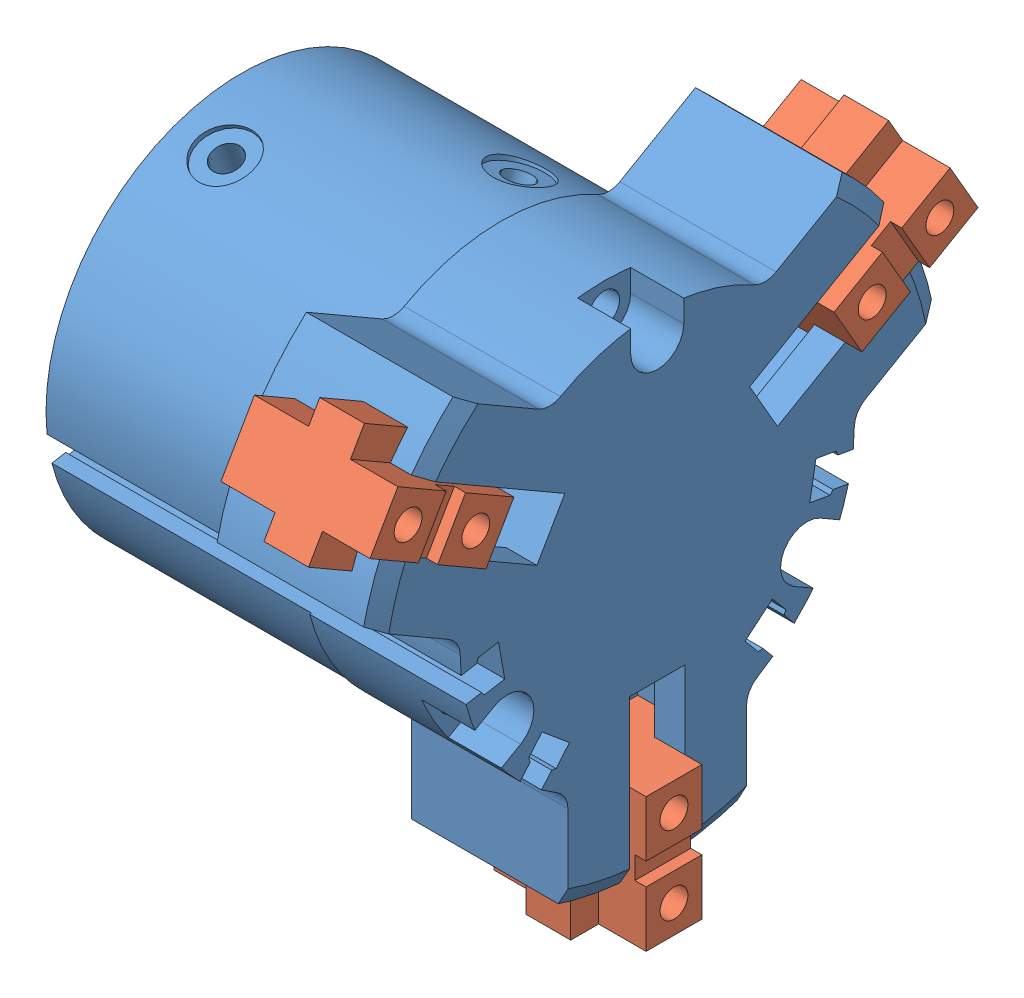
SolidWorks assembly MHSL3-50D, configuration MHSL3-50D. Lengths in mm.
Overall size (77.5 98.66 113.92).
4 component instances, 2 part files, 7 mates.
Components (placement in the parent):
- MHSL3-50D_MHSL-Body-1: MHSL3-50D_MHSL-Body [50] x (-1 0 0) z (0 0 -1) size (74.5 90.6 101.7)
- MHSL3-50D_MHSL-Finger-1: MHSL3-50D_MHSL-Finger [50] at (61 -48 0) x (-1 0 0) z (0 0 1) size (26.2 24 20)
- MHSL3-50D_MHSL-Finger-2: MHSL3-50D_MHSL-Finger [50] at (61 24 41.5692) x (-1 0 0) z (0 0.866025 -0.5) size (26.2 24 20)
- MHSL3-50D_MHSL-Finger-3: MHSL3-50D_MHSL-Finger [50] at (61 24 -41.5692) x (-1 0 0) z (0 -0.866025 -0.5) size (26.2 24 20)
Mates (geometry in assembly coordinates):
- Coincident1: coincident: plane of MHSL3-50D_MHSL-Body-1 through (0 0 0) normal (-1 0 0); plane of assembly through (0 0 0) normal (1 0 0)
- Coincident2: coincident: plane of MHSL3-50D_MHSL-Body-1 through (0 0 0) normal (0 1 0); plane of assembly through (0 0 0) normal (0 1 0)
- Coincident3: coincident: plane of MHSL3-50D_MHSL-Body-1 through (0 0 0) normal (0 0 -1); plane of assembly through (0 0 0) normal (0 0 1)
- Coincident4: coincident: plane of MHSL3-50D_MHSL-Body-1 through (61 -22 5) normal (1 0 0); plane of MHSL3-50D_MHSL-Finger-1 through (61 -60 5) normal (-1 0 0)
- Coincident6: coincident: plane of MHSL3-50D_MHSL-Body-1 through (0 0 0) normal (0 0 -1); plane of MHSL3-50D_MHSL-Finger-1 through (61 -48 0) normal (0 0 1)
- DO(GripperOpen): distance = 60 mm: plane of MHSL3-50D_MHSL-Body-1 through (0 0 0) normal (0 1 0); plane of MHSL3-50D_MHSL-Finger-1 through (77.5 -60 5) normal (0 -1 0)
- DC(GripperClose): distance = 46 mm: plane of MHSL3-50D_MHSL-Body-1 through (0 0 0) normal (0 1 0); plane of MHSL3-50D_MHSL-Finger-1 through (58 -42 4) normal (0 -1 0)
